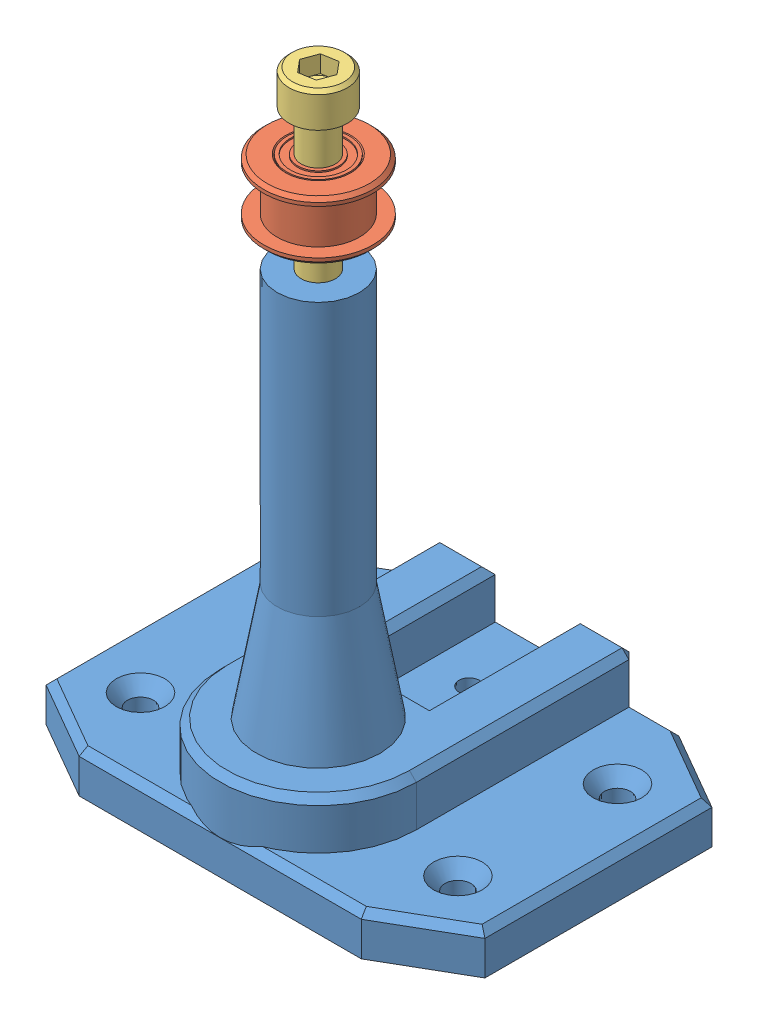
SolidWorks assembly platform idler mount assembly, configuration Default. Lengths in mm.
Overall size (64 95.2 46.3).
3 component instances, 3 part files, 4 mates.
Components (placement in the parent):
- platform rail mount-1: platform rail mount [Default] at origin size (64 69.7 46.3)
- GT2 idler pulley (5 mm bore) v1-1: GT2 idler pulley (5 mm bore) v1 [Default] at (-296.943 43.3009 284.1262) x (0.875501 0 -0.483216) z (0 -1 0) size (15.9 15.9 8.5)
- socket head cap screw_am-1: socket head cap screw_am [B18.3.1M - 5 x 0.8 x 50 Hex SHCS -- 22NHX] at (-296.943 55.3009 284.1262) x (0 -1 0) z (0.765843 0 -0.643027) size (55 8.5 8.5)
Mates (geometry in assembly coordinates):
- Concentric1: concentric aligned: cylinder of platform rail mount-1 through (-296.943 29.8009 284.1262) axis (0 -1 0) radius 6; cylinder of GT2 idler pulley (5 mm bore) v1-1 through (-296.943 43.3009 284.1262) axis (0 -1 0) radius 6
- Distance1: distance = 6 mm anti-aligned: plane of GT2 idler pulley (5 mm bore) v1-1 through (-296.943 35.8009 284.1262) normal (0 -1 0); plane of platform rail mount-1 through (-296.943 29.8009 284.1262) normal (0 1 0)
- Concentric2: concentric aligned: cylinder of platform rail mount-1 through (-296.943 29.8009 284.1262) axis (0 1 0) radius 2.1; cylinder of socket head cap screw_am-1 through (-296.943 87.0509 284.1262) axis (0 1 0) radius 4.25
- Distance2: distance = 6 mm anti-aligned: plane of socket head cap screw_am-1 through (-299.6759 50.3009 280.8714) normal (0 -1 0); plane of GT2 idler pulley (5 mm bore) v1-1 through (-296.943 44.3009 284.1262) normal (0 1 0)
